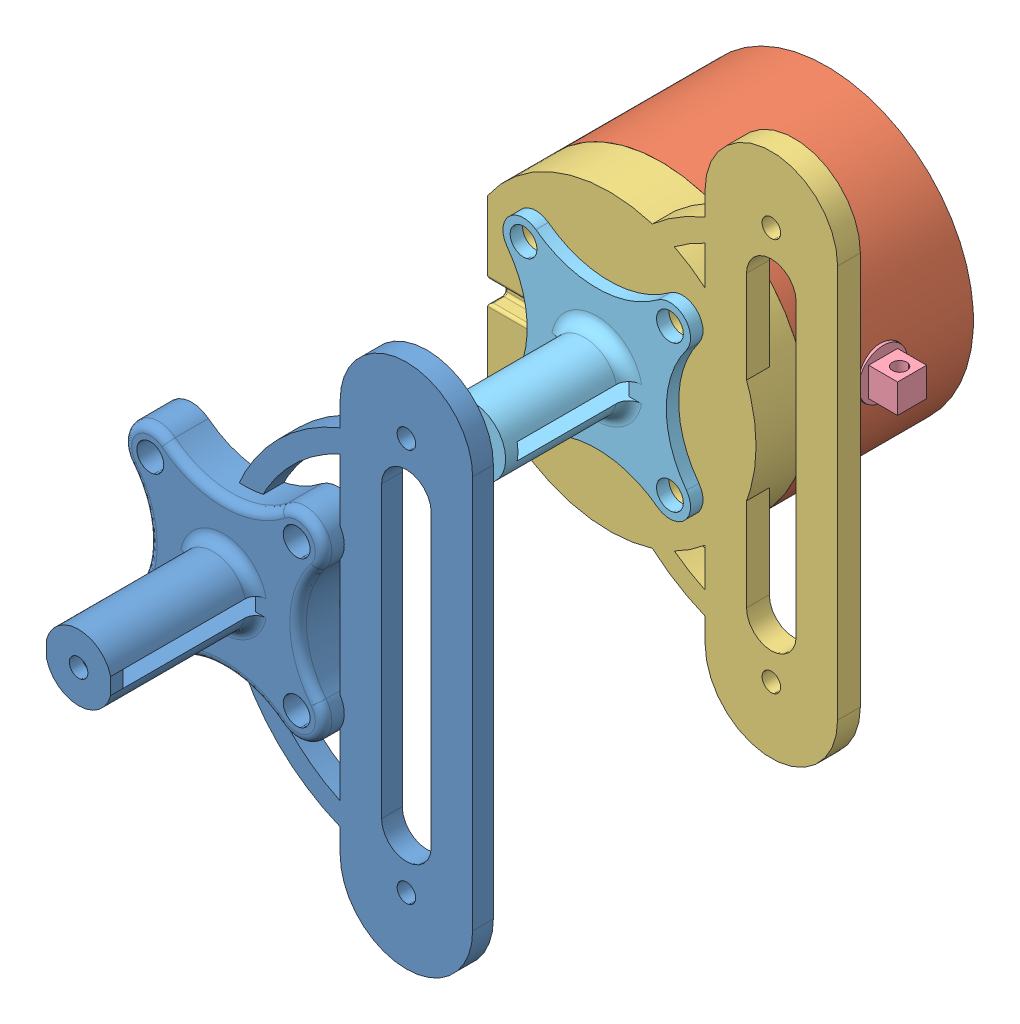
SolidWorks assembly Ensamblaje1, configuration Default. Lengths in mm.
Overall size (90.68 127 180.65).
5 component instances, 5 part files, 11 mates.
Components (placement in the parent):
- gripper1 v10-2: gripper1 v10 [Predeterminado] at (-152.7044 276.6838 330.6847) x (0 1 0) z (1 0 0) size (127 45 79.36)
- Base-1: Base [Predeterminado] at (-152.7044 276.6838 195.0304) size (71 71 40)
- Camara-1: Camara [Predeterminado] at (-152.7044 276.6838 240.0304) x (0 1 0) z (0 0 -1) size (127 84.51 47.5)
- Pestillo-1: Pestillo [Predeterminado] at (-149.5344 276.6838 217.0304) x (0 -1 0) z (1 0 0) size (11.8 11.8 72)
- Iman-1: Iman [Predeterminado] at (-152.7044 276.6838 247.5304) size (45.36 45.36 33)
Mates (geometry in assembly coordinates):
- Concéntrica1: concentric anti-aligned: cylinder of Base-1 through (-152.7044 276.6838 235.0304) axis (0 0 -1) radius 20; cylinder of Camara-1 through (-152.7044 276.6838 200.0304) axis (0 0 1) radius 19.85
- Coincidente2: coincident aligned: plane of Base-1 through (-182.0344 276.6838 235.0304) normal (-1 0 0); plane of Camara-1 through (-182.0344 256.6838 242.5304) normal (-1 0 0)
- Paralelo1: parallel aligned: plane of gripper1 v10-2 through (-129.5267 312.9718 330.6847) normal (-1 0 0); plane of Camara-1 through (-182.0344 256.6838 242.5304) normal (-1 0 0)
- Concéntrica2: concentric aligned: cylinder of Base-1 through (-117.2044 276.6838 217.0304) axis (-1 0 0) radius 6; cylinder of 39.8-1 through (-117.0344 276.6838 217.0304) axis (-1 0 0) radius 5.9
- Concéntrica3: concentric anti-aligned: cylinder of gripper1 v10-2 through (-152.7044 276.6838 340.6847) axis (0 0 1) radius 8; cylinder of Base-1 through (-152.7044 276.6838 235.0304) axis (0 0 -1) radius 20
- Coincidente5: coincident aligned: plane of Base-1 through (-182.0344 276.6838 235.0304) normal (-1 0 0); plane of 39.8-1 through (-182.0344 276.6838 217.0304) normal (-1 0 0)
- Paralelo2: parallel anti-aligned: plane of Base-1 through (-152.7044 276.6838 235.0304) normal (0 0 1); plane of 39.8-1 through (-110.0344 280.1838 213.5304) normal (0 0 -1)
- Coincidente9: coincident anti-aligned: plane of Camara-1 through (-152.7044 276.6838 247.5304) normal (0 0 1); plane of Iman-1 through (-152.7044 276.6838 247.5304) normal (0 0 -1)
- Concéntrica5: concentric anti-aligned: cylinder of Camara-1 through (-170.382 294.3615 235.0304) axis (0 0 1) radius 3.25; cylinder of Iman-1 through (-170.382 294.3615 250.5304) axis (0 0 -1) radius 3.25
- Concéntrica6: concentric anti-aligned: cylinder of Camara-1 through (-135.0267 259.0061 235.0304) axis (0 0 1) radius 3.25; cylinder of Iman-1 through (-135.0267 259.0061 250.5304) axis (0 0 -1) radius 3.25
- Concéntrica7: concentric anti-aligned: cylinder of Camara-1 through (-188.2044 276.6838 217.0304) axis (1 0 0) radius 6; cylinder of 39.8-1 through (-117.0344 276.6838 217.0304) axis (-1 0 0) radius 5.9
